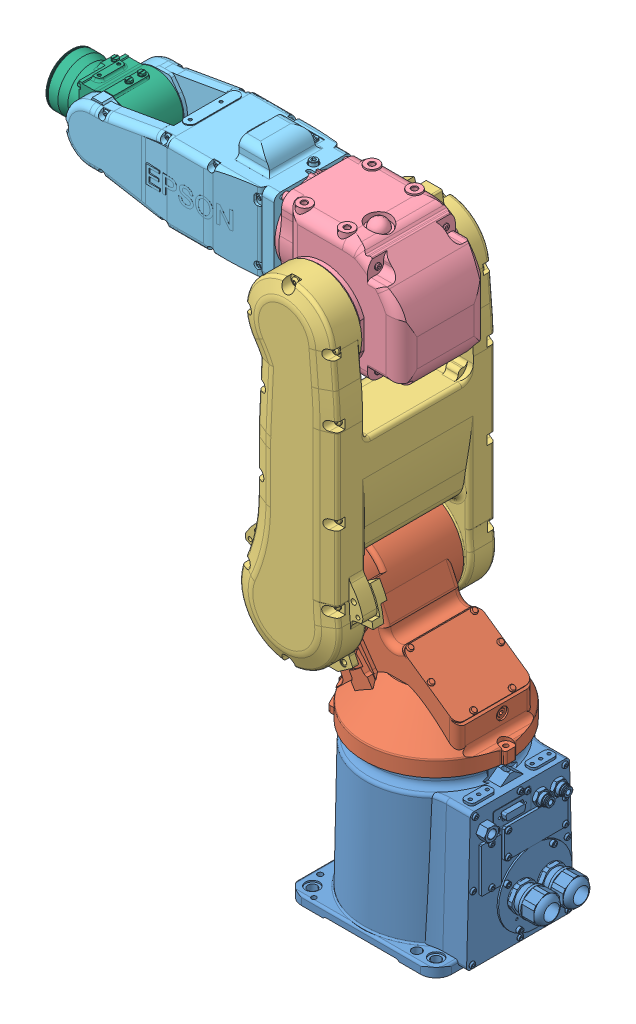
SolidWorks assembly S5_A701S, configuration Default. Lengths in mm.
Overall size (623.2 752.51 219.43).
7 component instances, 7 part files, 18 mates.
Components (placement in the parent):
- S5_BASE-1: S5_BASE [Default] at origin size (250.2 204.01 197)
- S5_ARM1-1: S5_ARM1 [Default] at (0 199 0) size (245.28 204.35 187)
- S5_ARM2-1: S5_ARM2 [Default] at (-88 330 0) size (164.19 450 219.43)
- S5_ARM3-1: S5_ARM3 [Default] at (-88 640 0) size (170.51 155.5 134.01)
- S5_ARM4-1: S5_ARM4 [Default] at (-393 680 0) size (273.14 125 114.1)
- S5_ARM5-1: S5_ARM5 [Default] at (-393 680 0) size (115.5 80.6 66)
- S5_ARM6-1: S5_ARM6 [Default] at (-473 680 0) size (29 48 48)
Mates (geometry in assembly coordinates):
- J1: planar angle = 0 rad aligned: plane of S5_BASE-1 through (0 0 0) normal (0 0 1); plane of S5_ARM1-1 through (0 199 0) normal (0 0 1)
- J2: planar angle = 0 rad aligned: plane of S5_ARM2-1 through (0 -88 330) normal (0 0 1); plane of S5_ARM1-1 through (0 0 199) normal (0 0 1)
- J3: planar angle = 0 rad aligned: plane of S5_ARM3-1 through (0 -88 640) normal (0 0 1); plane of S5_ARM2-1 through (0 -88 330) normal (0 0 1)
- J4: planar angle = 0 rad aligned: plane of ? through (0 -393 680) normal (0 0 1); plane of S5_ARM3-1 through (0 -88 640) normal (0 0 1)
- J5: planar angle = 0 rad aligned: plane of ? through (0 -393 680) normal (0 0 1); plane of ? through (0 -393 680) normal (0 0 1)
- J6: planar angle = 0 rad aligned: plane of ? through (0 -393 680) normal (0 0 1); plane of S5_ARM6-1 through (0 -473 680) normal (0 0 1)
- Concentric1: concentric aligned: cylinder of S5_BASE-1; cylinder of S5_ARM1-1
- Distance1: distance = 2.5 mm anti-aligned: plane of S5_BASE-1 through (0 75 196.5) normal (0 0 1); plane of S5_ARM1-1 through (-93.5 199 50) normal (0 -1 0)
- Concentric2: concentric anti-aligned: cone of S5_ARM1-1; cylinder of S5_ARM2-1
- Distance2: distance = 2 mm anti-aligned: plane of S5_ARM1-1 through (-88 381 55.5) normal (0 0 1); plane of S5_ARM2-1 through (-88 385 57.5) normal (0 0 -1)
- Concentric3: concentric aligned: cylinder of S5_ARM2-1; cylinder of S5_ARM3-1
- Distance3: distance = 2 mm anti-aligned: plane of S5_ARM3-1 through (-88 640 62.5) normal (0 0 1); plane of S5_ARM2-1 through (-88 640 64.5) normal (0 0 -1)
- Concentric4: concentric aligned: cylinder of S5_ARM3-1; cylinder of ?
- Distance4: distance = 1 mm anti-aligned: plane of ? through (-159.5 722 49) normal (1 0 0); plane of S5_ARM3-1 through (0 -158.5 680) normal (0 -1 0)
- Concentric5: concentric anti-aligned: cylinder of ?; cylinder of ?
- Distance5: distance = 1 mm anti-aligned: plane of ? through (-393 716 31) normal (0 0 -1); plane of ? through (-412.8 638.5 30) normal (0 0 1)
- Concentric6: concentric anti-aligned: circle of S5_ARM6-1; circle of ?
- Distance6: distance = 0.5 mm aligned: plane of ? through (0 -472.5 680) normal (0 -1 0); plane of S5_ARM6-1 through (0 -473 680) normal (0 -1 0)
